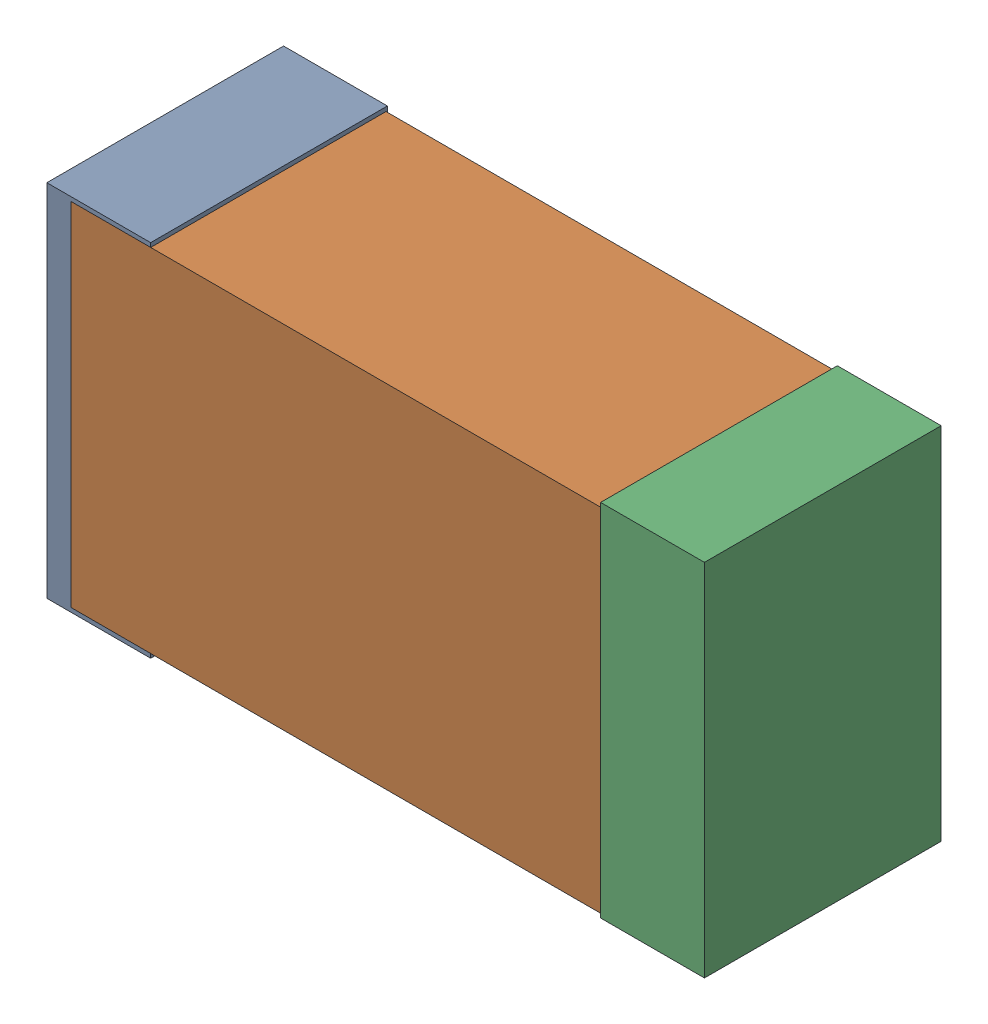
SolidWorks assembly FB4, configuration Default. Lengths in mm.
Overall size (2.38 1.3 0.85).
6 component instances, 2 part files, 0 mates.
Components (placement in the parent):
- 384311232-1: 384311232 [Default] at (20.209 43.18 -1.9574) size (0.38 1.3 0.85)
  - Extruded_8-1: Extruded_8 [Default] at origin size (0.38 1.3 0.85)
- 384311360-1: 384311360 [Default] at (21.209 43.18 -1.9524) size (2.2 1.27 0.85)
  - Extruded_9-1: Extruded_9 [Default] at origin size (2.2 1.27 0.85)
- 384311232-2: 384311232 [Default] at (22.209 43.18 -1.9574) size (0.38 1.3 0.85)
  - Extruded_8-1: Extruded_8 [Default] at origin size (0.38 1.3 0.85)
